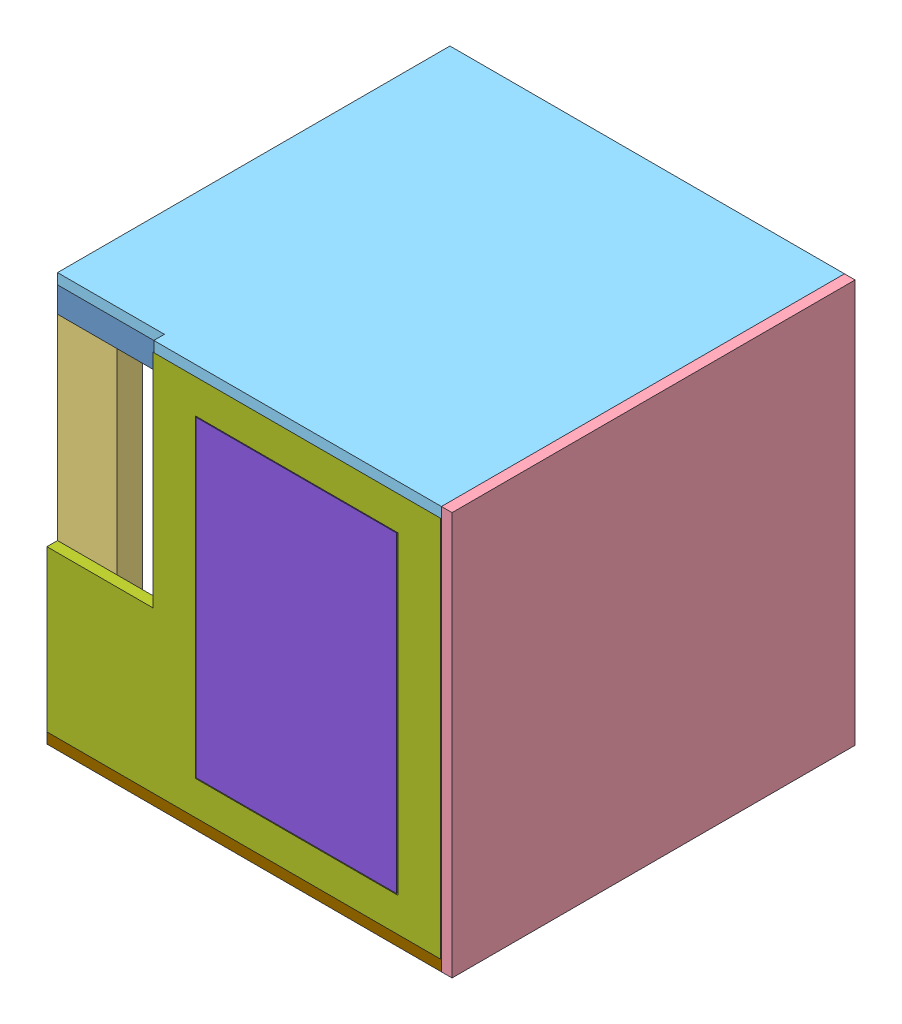
SolidWorks assembly rear standing cube, configuration Default. Lengths in mm.
Overall size (606.43 603.25 603.25).
20 component instances, 9 part files, 57 mates.
Components (placement in the parent):
- 24in 2x4-1: 24in 2x4 [Default] at (-233.9335 -35.9504 18.5366) size (590.55 38.1 88.9)
- 17in 2x4-1: 17in 2x4 [Default] at (-145.0335 -35.9504 -70.3634) x (0 0 -1) z (1 0 0) size (393.7 38.1 88.9)
- 17in 2x4-2: 17in 2x4 [Default] at (267.7165 -35.9504 -464.0634) x (0 0 1) z (-1 0 0) size (393.7 38.1 88.9)
- 24in 2x4-2: 24in 2x4 [Default] at (-233.9335 -35.9504 -464.0634) size (590.55 38.1 88.9)
- 21in 2x4-1: 21in 2x4 [Default] at (356.6165 -531.2504 18.5366) x (0 1 0) z (0 0 1) size (495.3 38.1 88.9)
- 21in 2x4-2: 21in 2x4 [Default] at (-233.9335 -531.2504 18.5366) x (0 1 0) z (-1 0 0) size (495.3 38.1 88.9)
- 21in 2x4-3: 21in 2x4 [Default] at (318.5165 -35.9504 -464.0634) x (0 -1 0) z (0 0 1) size (495.3 38.1 88.9)
- 21in 2x4-4: 21in 2x4 [Default] at (-233.9335 -35.9504 -464.0634) x (0 -1 0) z (0 0 1) size (495.3 38.1 88.9)
- 24in 2x4-3: 24in 2x4 [Default] at (-233.9335 -569.3504 18.5366) size (590.55 38.1 88.9)
- 24in 2x4-4: 24in 2x4 [Default] at (-233.9335 -569.3504 -464.0634) size (590.55 38.1 88.9)
- 17in 2x4-4: 17in 2x4 [Default] at (356.6165 -569.3504 -70.3634) x (0 0 -1) z (1 0 0) size (393.7 38.1 88.9)
- 17in 2x4-5: 17in 2x4 [Default] at (-145.0335 -569.3504 -70.3634) x (0 0 -1) z (1 0 0) size (393.7 38.1 88.9)
- 2x2 .75-1: 2x2 .75 [Default] at (372.4915 18.0246 -568.8384) x (0 -1 0) z (0 0 -1) size (603.25 15.88 603.25)
- 24x23.5 .75-2: 24x23.5 .75 [Default] at (356.6165 18.0246 34.4116) x (-1 0 0) z (0 0 1) size (590.55 15.88 603.25)
- 23.25x22.50 .75-1: 23.25x22.50 .75 [Default] at (-233.9335 -569.3504 -552.9634) x (0 1 0) z (-1 0 0) size (571.5 15.88 590.55)
- 22.5x16.95 .75-1: 22.5x16.95 .75 [Default] at (-75.1835 2.1496 18.5366) x (0 -1 0) z (-1 0 0) size (571.5 15.88 589.28)
- 21in 2x4-5: 21in 2x4 [Default] at (293.1165 -531.2504 18.5366) x (0 1 0) z (0 0 1) size (495.3 38.1 88.9)
- 21in 2x4-6: 21in 2x4 [Default] at (27.6865 -531.2504 18.5366) x (0 1 0) z (0 0 1) size (495.3 38.1 88.9)
- panel door-1: panel door [Default] at (-10.4135 -517.2804 34.4116) x (0 1 0) z (-1 0 0) size (467.36 15.88 299.72)
- 24x23.25 .75-1: 24x23.25 .75 [Default] at (-233.9335 -585.2254 34.4116) size (590.55 15.88 603.25)
Mates (geometry in assembly coordinates):
- Coincident1: coincident anti-aligned: plane of 24in 2x4-1 through (-233.9335 2.1496 -70.3634) normal (0 0 -1); plane of 17in 2x4-1 through (-145.0335 2.1496 -70.3634) normal (0 0 1)
- Coincident2: coincident aligned: plane of 24in 2x4-1 through (-233.9335 2.1496 18.5366) normal (-1 0 0); plane of 17in 2x4-1 through (-233.9335 2.1496 -70.3634) normal (-1 0 0)
- Coincident3: coincident aligned: plane of 24in 2x4-1 through (-233.9335 -35.9504 -70.3634) normal (0 -1 0); plane of 17in 2x4-1 through (-233.9335 -35.9504 -70.3634) normal (0 -1 0)
- Coincident4: coincident anti-aligned: plane of 17in 2x4-1 through (-145.0335 2.1496 -464.0634) normal (0 0 -1); plane of 24in 2x4-2 through (-233.9335 2.1496 -464.0634) normal (0 0 1)
- Coincident5: coincident aligned: plane of 17in 2x4-1 through (-233.9335 2.1496 -70.3634) normal (-1 0 0); plane of 24in 2x4-2 through (-233.9335 2.1496 -464.0634) normal (-1 0 0)
- Coincident6: coincident aligned: plane of 17in 2x4-1 through (-233.9335 -35.9504 -70.3634) normal (0 -1 0); plane of 24in 2x4-2 through (-233.9335 -35.9504 -552.9634) normal (0 -1 0)
- Coincident7: coincident anti-aligned: plane of 24in 2x4-1 through (-233.9335 2.1496 -70.3634) normal (0 0 -1); plane of 17in 2x4-2 through (267.7165 2.1496 -70.3634) normal (0 0 1)
- Coincident8: coincident aligned: plane of 17in 2x4-2 through (356.6165 2.1496 -464.0634) normal (1 0 0); plane of 24in 2x4-2 through (356.6165 2.1496 -464.0634) normal (1 0 0)
- Coincident9: coincident aligned: plane of 17in 2x4-2 through (356.6165 -35.9504 -464.0634) normal (0 -1 0); plane of 24in 2x4-2 through (-233.9335 -35.9504 -552.9634) normal (0 -1 0)
- Coincident10: coincident aligned: plane of 24in 2x4-1 through (356.6165 2.1496 18.5366) normal (1 0 0); plane of 21in 2x4-1 through (356.6165 -531.2504 -70.3634) normal (1 0 0)
- Coincident11: coincident aligned: plane of 24in 2x4-1 through (-233.9335 2.1496 18.5366) normal (0 0 1); plane of 21in 2x4-1 through (318.5165 -531.2504 18.5366) normal (0 0 1)
- Coincident12: coincident anti-aligned: plane of 24in 2x4-1 through (-233.9335 -35.9504 -70.3634) normal (0 -1 0); plane of 21in 2x4-1 through (318.5165 -35.9504 18.5366) normal (0 1 0)
- Coincident15: coincident anti-aligned: plane of 24in 2x4-1 through (-233.9335 -35.9504 -70.3634) normal (0 -1 0); plane of 21in 2x4-2 through (-233.9335 -35.9504 -19.5634) normal (0 1 0)
- Coincident16: coincident aligned: plane of 24in 2x4-2 through (356.6165 2.1496 -464.0634) normal (1 0 0); plane of 21in 2x4-3 through (356.6165 -35.9504 -552.9634) normal (1 0 0)
- Coincident17: coincident anti-aligned: plane of 17in 2x4-2 through (356.6165 -35.9504 -464.0634) normal (0 -1 0); plane of 21in 2x4-3 through (356.6165 -35.9504 -464.0634) normal (0 1 0)
- Coincident18: coincident aligned: plane of 24in 2x4-2 through (-233.9335 2.1496 -552.9634) normal (0 0 -1); plane of 21in 2x4-3 through (356.6165 -35.9504 -552.9634) normal (0 0 -1)
- Coincident19: coincident aligned: plane of 17in 2x4-1 through (-233.9335 2.1496 -70.3634) normal (-1 0 0); plane of 21in 2x4-4 through (-233.9335 -35.9504 -552.9634) normal (-1 0 0)
- Coincident20: coincident anti-aligned: plane of 24in 2x4-2 through (-233.9335 -35.9504 -552.9634) normal (0 -1 0); plane of 21in 2x4-4 through (-195.8335 -35.9504 -464.0634) normal (0 1 0)
- Coincident21: coincident aligned: plane of 24in 2x4-2 through (-233.9335 2.1496 -552.9634) normal (0 0 -1); plane of 21in 2x4-4 through (-195.8335 -35.9504 -552.9634) normal (0 0 -1)
- Coincident25: coincident aligned: plane of 21in 2x4-4 through (-233.9335 -35.9504 -552.9634) normal (-1 0 0); plane of 24in 2x4-4 through (-233.9335 -531.2504 -464.0634) normal (-1 0 0)
- Coincident26: coincident anti-aligned: plane of 21in 2x4-3 through (356.6165 -531.2504 -464.0634) normal (0 -1 0); plane of 24in 2x4-4 through (-233.9335 -531.2504 -552.9634) normal (0 1 0)
- Coincident27: coincident aligned: plane of 21in 2x4-3 through (356.6165 -35.9504 -552.9634) normal (0 0 -1); plane of 24in 2x4-4 through (-233.9335 -531.2504 -552.9634) normal (0 0 -1)
- Coincident28: coincident anti-aligned: plane of 21in 2x4-1 through (318.5165 -531.2504 18.5366) normal (0 -1 0); plane of 24in 2x4-3 through (-233.9335 -531.2504 -70.3634) normal (0 1 0)
- Coincident29: coincident aligned: plane of 21in 2x4-1 through (318.5165 -531.2504 18.5366) normal (0 0 1); plane of 24in 2x4-3 through (-233.9335 -531.2504 18.5366) normal (0 0 1)
- Coincident31: coincident anti-aligned: plane of 24in 2x4-4 through (-233.9335 -531.2504 -464.0634) normal (0 0 1); plane of 17in 2x4-5 through (-145.0335 -531.2504 -464.0634) normal (0 0 -1)
- Coincident32: coincident aligned: plane of 24in 2x4-3 through (-233.9335 -531.2504 18.5366) normal (-1 0 0); plane of 17in 2x4-5 through (-233.9335 -531.2504 -70.3634) normal (-1 0 0)
- Coincident33: coincident aligned: plane of 24in 2x4-3 through (-233.9335 -531.2504 -70.3634) normal (0 1 0); plane of 17in 2x4-5 through (-233.9335 -531.2504 -70.3634) normal (0 1 0)
- Coincident34: coincident anti-aligned: plane of 24in 2x4-4 through (-233.9335 -531.2504 -464.0634) normal (0 0 1); plane of 17in 2x4-4 through (356.6165 -531.2504 -464.0634) normal (0 0 -1)
- Coincident35: coincident aligned: plane of 24in 2x4-4 through (-233.9335 -531.2504 -552.9634) normal (0 1 0); plane of 17in 2x4-4 through (267.7165 -531.2504 -70.3634) normal (0 1 0)
- Coincident36: coincident aligned: plane of 24in 2x4-4 through (356.6165 -531.2504 -464.0634) normal (1 0 0); plane of 17in 2x4-4 through (356.6165 -531.2504 -70.3634) normal (1 0 0)
- Coincident37: coincident anti-aligned: plane of 21in 2x4-3 through (356.6165 -35.9504 -552.9634) normal (1 0 0); plane of 2x2 .75-1 through (356.6165 18.0246 37.5866) normal (-1 0 0)
- Distance2: distance = 587.375 mm anti-aligned: plane of 21in 2x4-3 through (356.6165 -35.9504 -552.9634) normal (0 0 -1); plane of 2x2 .75-1 through (356.6165 18.0246 34.4116) normal (0 0 1)
- Distance3: distance = 587.375 mm anti-aligned: plane of 2x2 .75-1 through (356.6165 18.0246 -568.8384) normal (0 1 0); plane of 17in 2x4-4 through (267.7165 -569.3504 -70.3634) normal (0 -1 0)
- Coincident57: coincident anti-aligned: plane of 17in 2x4-2 through (356.6165 2.1496 -464.0634) normal (0 1 0); plane of 24x23.5 .75-2 through (356.6165 2.1496 -568.8384) normal (0 -1 0)
- Coincident58: coincident anti-aligned: plane of 2x2 .75-1 through (356.6165 18.0246 37.5866) normal (-1 0 0); plane of 24x23.5 .75-2 through (356.6165 2.1496 34.4116) normal (1 0 0)
- Coincident68: coincident aligned: plane of 24in 2x4-1 through (-233.9335 2.1496 18.5366) normal (-1 0 0); plane of 21in 2x4-2 through (-233.9335 -531.2504 -19.5634) normal (-1 0 0)
- Coincident69: coincident aligned: plane of 24in 2x4-1 through (-233.9335 2.1496 18.5366) normal (0 0 1); plane of 21in 2x4-2 through (-145.0335 -531.2504 18.5366) normal (0 0 1)
- Coincident71: coincident anti-aligned: plane of 24in 2x4-1 through (-233.9335 -35.9504 -70.3634) normal (0 -1 0); plane of 21in 2x4-5 through (255.0165 -35.9504 18.5366) normal (0 1 0)
- Coincident73: coincident aligned: plane of 24in 2x4-1 through (-233.9335 2.1496 18.5366) normal (0 0 1); plane of 21in 2x4-5 through (255.0165 -531.2504 18.5366) normal (0 0 1)
- Distance4: distance = 25.4 mm anti-aligned: plane of 21in 2x4-1 through (318.5165 -531.2504 -70.3634) normal (-1 0 0); plane of 21in 2x4-5 through (293.1165 -531.2504 -70.3634) normal (1 0 0)
- Coincident75: coincident anti-aligned: plane of 24in 2x4-1 through (-233.9335 -35.9504 -70.3634) normal (0 -1 0); plane of 21in 2x4-6 through (-10.4135 -35.9504 18.5366) normal (0 1 0)
- Coincident76: coincident aligned: plane of 24in 2x4-1 through (-233.9335 2.1496 18.5366) normal (0 0 1); plane of 21in 2x4-6 through (-10.4135 -531.2504 18.5366) normal (0 0 1)
- Distance5: distance = 63.5 mm aligned: plane of 21in 2x4-6 through (-10.4135 -531.2504 -70.3634) normal (-1 0 0); plane of 24x23.5 .75-2 through (-73.9135 2.1496 34.4116) normal (-1 0 0)
- Coincident80: coincident anti-aligned: plane of 21in 2x4-2 through (-145.0335 -531.2504 18.5366) normal (0 0 1); plane of 22.5x16.95 .75-1 through (355.3465 2.1496 18.5366) normal (0 0 -1)
- Coincident81: coincident aligned: plane of 21in 2x4-2 through (-233.9335 -531.2504 -19.5634) normal (-1 0 0); plane of 22.5x16.95 .75-1 through (-233.9335 -283.6004 -418.3615) normal (-1 0 0)
- Coincident82: coincident anti-aligned: plane of 24x23.5 .75-2 through (356.6165 2.1496 -568.8384) normal (0 -1 0); plane of 22.5x16.95 .75-1 through (-75.1835 2.1496 34.4116) normal (0 1 0)
- Coincident88: coincident aligned: plane of 17in 2x4-5 through (-233.9335 -531.2504 -70.3634) normal (-1 0 0); plane of 24x23.25 .75-1 through (-233.9335 -569.3504 34.4116) normal (-1 0 0)
- Coincident91: coincident anti-aligned: plane of 2x2 .75-1 through (356.6165 18.0246 37.5866) normal (-1 0 0); plane of 23.25x22.50 .75-1 through (356.6165 -569.3504 -568.8384) normal (1 0 0)
- Coincident93: coincident anti-aligned: plane of 24in 2x4-3 through (356.6165 -531.2504 18.5366) normal (1 0 0); plane of 2x2 .75-1 through (356.6165 18.0246 37.5866) normal (-1 0 0)
- Coincident94: coincident anti-aligned: plane of 17in 2x4-4 through (267.7165 -569.3504 -70.3634) normal (0 -1 0); plane of 24x23.25 .75-1 through (-233.9335 -569.3504 -568.8384) normal (0 1 0)
- Coincident95: coincident aligned: plane of 22.5x16.95 .75-1 through (355.3465 2.1496 34.4116) normal (0 0 1); plane of 24x23.25 .75-1 through (-233.9335 -569.3504 34.4116) normal (0 0 1)
- Coincident96: coincident anti-aligned: plane of 24x23.5 .75-2 through (356.6165 2.1496 -568.8384) normal (0 -1 0); plane of 23.25x22.50 .75-1 through (-233.9335 2.1496 -568.8384) normal (0 1 0)
- Coincident97: coincident anti-aligned: plane of 21in 2x4-5 through (255.0165 -531.2504 18.5366) normal (0 0 1); plane of panel door-1 through (289.3065 -517.2804 18.5366) normal (0 0 -1)
- Distance6: distance = 1.27 mm anti-aligned: plane of panel door-1 through (-10.4135 -49.9204 18.5366) normal (0 1 0); plane of 22.5x16.95 .75-1 through (-11.6835 -48.6504 34.4116) normal (0 -1 0)
- Distance8: distance = 1.27 mm anti-aligned: plane of panel door-1 through (-10.4135 -517.2804 18.5366) normal (-1 0 0); plane of 22.5x16.95 .75-1 through (-11.6835 -48.6504 34.4116) normal (1 0 0)
- Coincident100: coincident anti-aligned: plane of 21in 2x4-3 through (356.6165 -35.9504 -552.9634) normal (0 0 -1); plane of 23.25x22.50 .75-1 through (356.6165 -569.3504 -552.9634) normal (0 0 1)
- Coincident101: coincident aligned: plane of 24x23.5 .75-2 through (356.6165 2.1496 34.4116) normal (0 0 1); plane of 22.5x16.95 .75-1 through (355.3465 2.1496 34.4116) normal (0 0 1)
